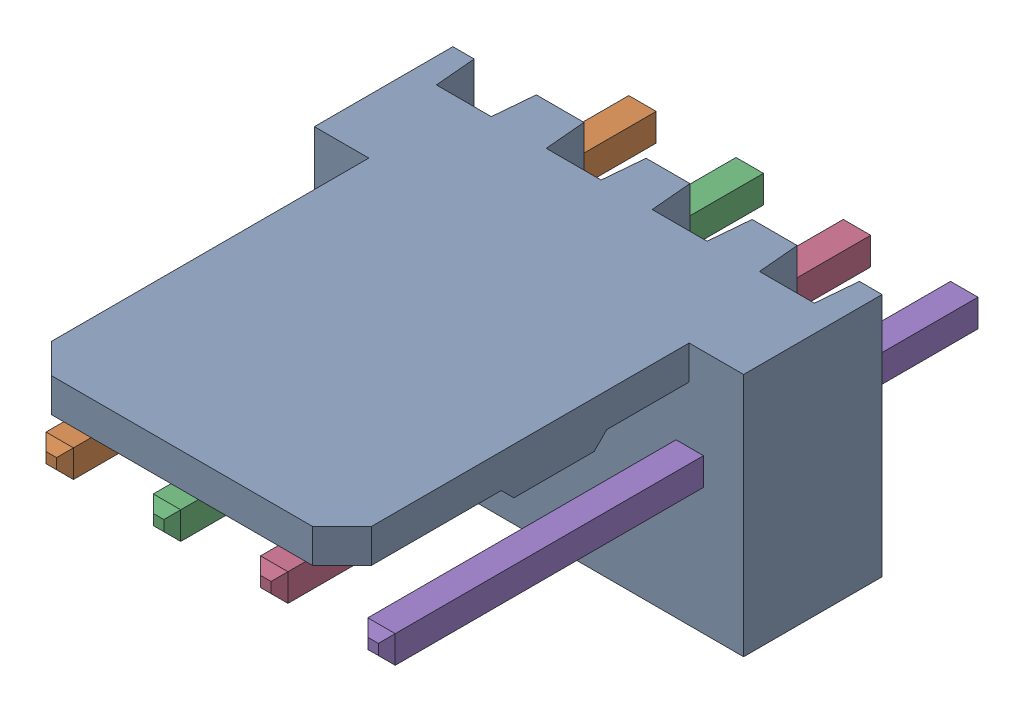
SolidWorks assembly Molex PCB 4 pin v3, configuration Default. Lengths in mm.
Overall size (10.16 5.79 14.92).
5 component instances, 2 part files, 0 mates.
Components (placement in the parent):
- BASE9710016-1: BASE9710016 [Default] at (2.54 2.895 -8.22) size (10.16 5.79 11.5)
- PINO9710016-1: PINO9710016 [Default] at (1.27 3.325 -0.72) size (0.65 0.65 14.2)
- PINO9710016-2: PINO9710016 [Default] at (3.81 3.325 -0.72) size (0.65 0.65 14.2)
- PINO9710016-3: PINO9710016 [Default] at (6.35 3.325 -0.72) size (0.65 0.65 14.2)
- PINO9710016-4: PINO9710016 [Default] at (8.89 3.325 -0.72) size (0.65 0.65 14.2)
